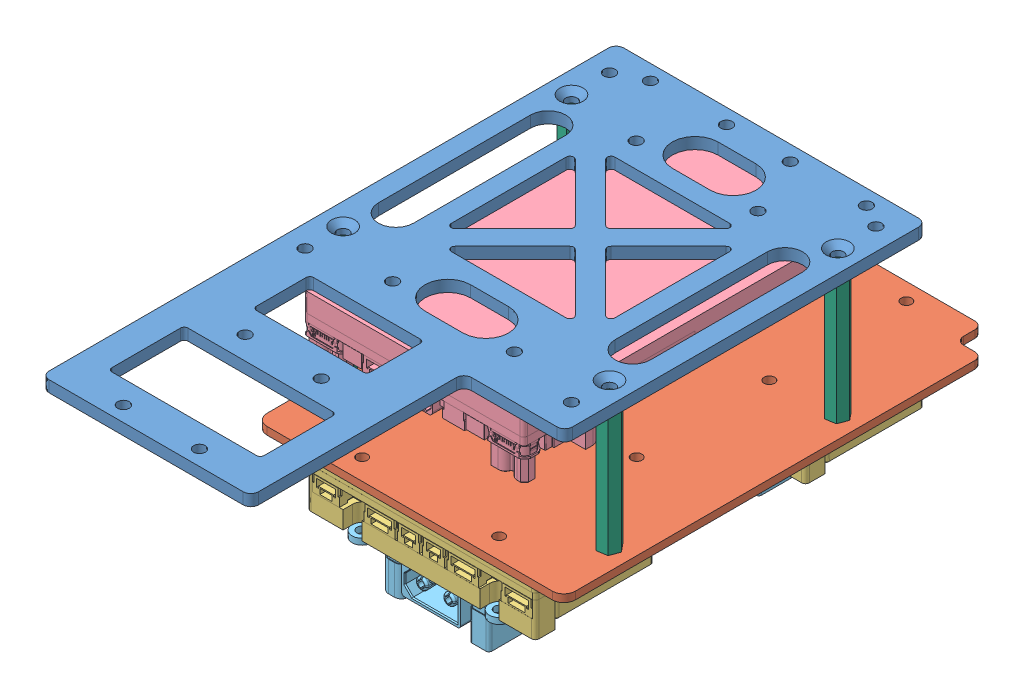
SolidWorks assembly 电子元件部分, configuration 默认. Lengths in mm.
Overall size (81.5 66.89 173).
11 component instances, 6 part files, 27 mates.
Components (placement in the parent):
- 开发板安装板-1: 开发板安装板 [默认] at origin size (81.5 3 151)
- c板安装板2-1: c板安装板2 [默认] at (-14.25 -37 -3.5) size (81 2 117)
- 开发板C型-1: 开发板C型 [默认] at (-35.9297 -57.6 -64.1005) x (0 0 -1) z (0 -1 0) size (41.04 60.33 16.3)
- 开发板C型-2: 开发板C型 [默认] at (-35.9297 -57.6 6.8995) x (0 0 -1) z (0 -1 0) size (41.04 60.33 16.3)
- 开发板A型-3: 开发板A型 [默认] at (-13.75 303.3989 207.4) x (-1 0 0) z (0 1 0) size (58.4 85.42 16.4)
- 3D_PCB_robomaster电调中心板_2023-11-26-6: 3D_PCB_robomaster电调中心板_2023-11-26 [默认] at (-41.6481 -51.6 -89.9462) x (1 0 0) z (0 -1 0) size (41.38 41.38 13.7)
- 3D_PCB_robomaster电调中心板_2023-11-26-7: 3D_PCB_robomaster电调中心板_2023-11-26 [默认] at (-41.7161 -51.6 -160.8782) x (1 0 0) z (0 -1 0) size (41.38 41.38 13.7)
- 304不锈钢柱-9: 304不锈钢柱 [M3*35] at (-49.25 -17.5 -22.5) x (0.996626 0 0.082078) z (0 1 0) size (5.43 4.7 35)
- 304不锈钢柱-10: 304不锈钢柱 [M3*35] at (20.75 -17.5 -22.5) x (0.986734 0 -0.162344) z (0 1 0) size (5.43 4.7 35)
- 304不锈钢柱-11: 304不锈钢柱 [M3*35] at (-49.25 -17.5 37.5) x (0.996626 0 0.082078) z (0 1 0) size (5.43 4.7 35)
- 304不锈钢柱-12: 304不锈钢柱 [M3*35] at (20.75 -17.5 37.5) x (0.351277 0 -0.936272) z (0 1 0) size (5.43 4.7 35)
Mates (geometry in assembly coordinates):
- 重合10: coincident anti-aligned: plane of c板安装板2-1 through (-14.25 -37 -3.5) normal (0 -1 0); plane of 开发板C型-1 through (-14.25 -37 -39.5) normal (0 1 0)
- 宽度5: width aligned: plane of c板安装板2-1 through (-54.75 -35 55) normal (-1 0 0); plane of 开发板C型-1 through (26.25 -35 55) normal (1 0 0); plane of c板安装板2-1 through (-44.25 -37 -39.5) normal (-1 0 0); plane of 开发板C型-1 through (15.75 -37 -19) normal (1 0 0)
- 重合11: coincident aligned: plane of 开发板C型-1 through (15.9734 -49.1 -50.6083) normal (0.999848 0.017452 0); plane of 开发板C型-2 through (15.9734 -49.1 20.3917) normal (0.999848 0.017452 0)
- 重合12: coincident aligned: plane of 开发板C型-1 through (-14.25 -51.6 -39.5) normal (0 -1 0); plane of 开发板C型-2 through (-14.25 -51.6 31.5) normal (0 -1 0)
- 重合42: coincident anti-aligned: plane of 开发板C型-2 through (-14.25 -51.6 31.5) normal (0 -1 0); plane of 3D_PCB_robomaster电调中心板_2023-11-26-6 through (-14.2134 -51.6 31.4626) normal (0 1 0)
- 同心13: concentric aligned: cylinder of 开发板C型-2 through (-32.25 -42.6 49.5) axis (0 1 0) radius 2.5; cylinder of 3D_PCB_robomaster电调中心板_2023-11-26-6 through (-32.25 -51.6 49.5) axis (0 1 0) radius 2.6391
- 重合43: coincident anti-aligned: plane of 开发板安装板-1 through (0 0 0) normal (0 -1 0); plane of 开发板A型-3 through (-14.25 0 11.5) normal (0 1 0)
- 宽度11: width aligned: plane of 开发板安装板-1 through (26.5 0 -40) normal (1 0 0); plane of 开发板安装板-1 through (-55 3 0) normal (-1 0 0); plane of 开发板A型-3 through (14.75 109.9029 -31) normal (1 0 0); plane of 开发板A型-3 through (-43.25 109.9029 -31) normal (-1 0 0)
- 平行4: parallel aligned: plane of 开发板安装板-1 through (26.5 0 -40) normal (1 0 0); plane of c板安装板2-1 through (26.25 -35 55) normal (1 0 0)
- 平行5: parallel aligned: plane of 开发板C型-2 through (-29.75 -42.6 52) normal (0 0 1); plane of 3D_PCB_robomaster电调中心板_2023-11-26-6 through (-29.5195 -51.6 49.4873) normal (0 0 1)
- 同心16: concentric anti-aligned: cylinder of 开发板C型-1 through (3.75 -42.6 -57.5) axis (0 1 0) radius 2.5; cylinder of 3D_PCB_robomaster电调中心板_2023-11-26-7 through (3.75 -51.6 -57.5) axis (0 -1 0) radius 1.35
- 重合45: coincident anti-aligned: plane of 开发板C型-1 through (-14.25 -51.6 -39.5) normal (0 -1 0); plane of 3D_PCB_robomaster电调中心板_2023-11-26-7 through (-14.2815 -51.6 -39.4693) normal (0 1 0)
- 平行7: parallel aligned: plane of 开发板C型-1 through (1.25 -42.6 -60) normal (0 0 -1); plane of 3D_PCB_robomaster电调中心板_2023-11-26-7 through (1.083 -51.6 -57.4873) normal (0 0 -1)
- 距离7: distance = 1 mm aligned: plane of 开发板A型-3 through (14.75 109.9029 54) normal (0 0 1); plane of 开发板安装板-1 through (0 3 55) normal (0 0 1)
- 重合46: coincident anti-aligned: plane of c板安装板2-1 through (-14.25 -35 -3.5) normal (0 1 0); plane of 304不锈钢柱-9 through (-49.25 -35 -22.5) normal (0 -1 0)
- 重合47: coincident anti-aligned: plane of 开发板安装板-1 through (0 0 0) normal (0 -1 0); plane of 304不锈钢柱-9 through (-49.25 0 -22.5) normal (0 1 0)
- 重合48: coincident anti-aligned: plane of c板安装板2-1 through (-14.25 -35 -3.5) normal (0 1 0); plane of 304不锈钢柱-11 through (-49.25 -35 37.5) normal (0 -1 0)
- 重合49: coincident anti-aligned: plane of 开发板安装板-1 through (0 0 0) normal (0 -1 0); plane of 304不锈钢柱-10 through (20.75 0 -22.5) normal (0 1 0)
- 重合50: coincident anti-aligned: plane of c板安装板2-1 through (-14.25 -35 -3.5) normal (0 1 0); plane of 304不锈钢柱-12 through (20.75 -35 37.5) normal (0 -1 0)
- 同心18: concentric anti-aligned: cone of 开发板安装板-1 through (20.75 3 37.5) axis (0 -1 0); cylinder of 304不锈钢柱-12 through (20.75 0 37.5) axis (0 1 0) radius 1.25
- 同心19: concentric aligned: circle of 开发板安装板-1; cylinder of 304不锈钢柱-10 through (20.75 0 -22.5) axis (0 1 0) radius 1.25
- 同心20: concentric aligned: circle of 开发板安装板-1; cylinder of 304不锈钢柱-9 through (-49.25 0 -22.5) axis (0 1 0) radius 1.25
- 同心21: concentric aligned: circle of 开发板安装板-1; cylinder of 304不锈钢柱-11 through (-49.25 0 37.5) axis (0 1 0) radius 1.25
- 宽度12: width aligned: plane of 开发板安装板-1 through (26.5 0 -40) normal (1 0 0); plane of c板安装板2-1 through (-55 3 0) normal (-1 0 0); plane of 开发板安装板-1 through (26.25 -35 55) normal (1 0 0); plane of c板安装板2-1 through (-54.75 -35 55) normal (-1 0 0)
- 重合52: coincident aligned: plane of 开发板安装板-1 through (0 3 55) normal (0 0 1); plane of c板安装板2-1 through (-54.75 -35 55) normal (0 0 1)
- 距离8: distance = 30 mm anti-aligned: plane of 开发板C型-2 through (11.75 -37 11) normal (0 0 -1); plane of 开发板C型-1 through (-44.25 -37 -19) normal (0 0 1)
- 距离9: distance = 2 mm aligned: plane of 开发板C型-1 through (11.75 -37 -60) normal (0 0 -1); plane of c板安装板2-1 through (-54.75 -35 -62) normal (0 0 -1)
